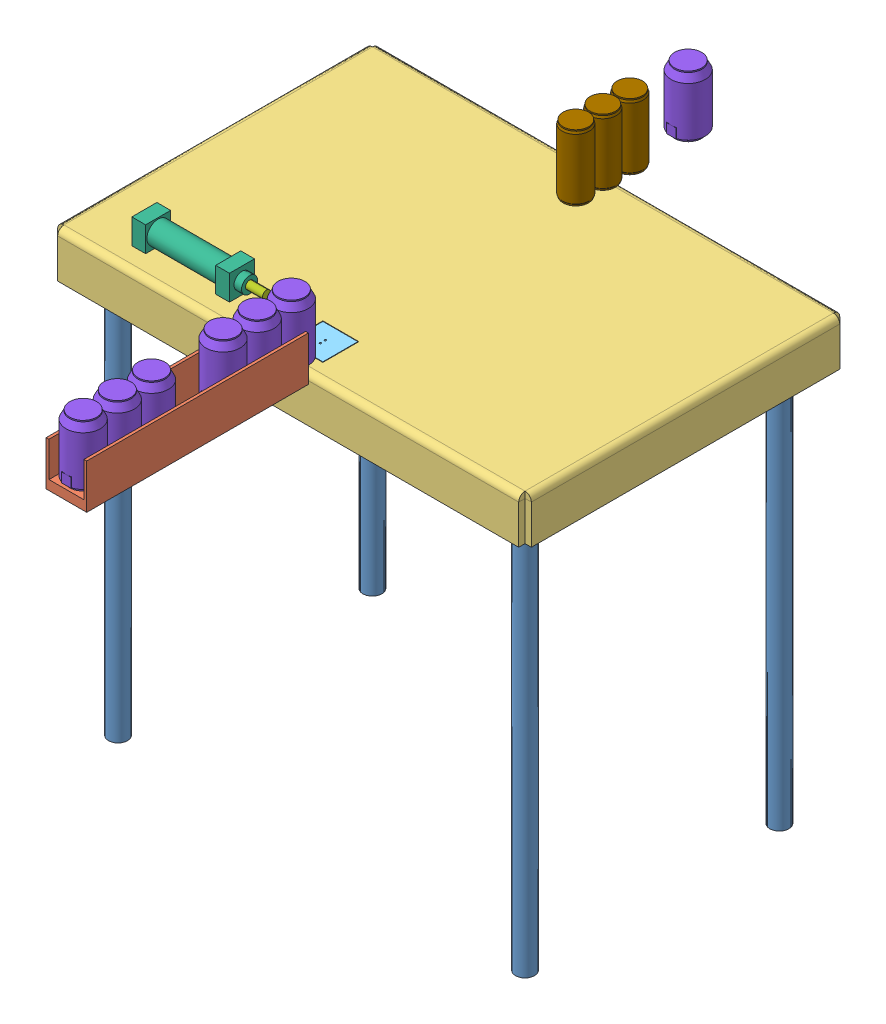
SolidWorks assembly Full_Assembly_v3, configuration Default. Lengths in mm.
Overall size (946.15 1065.21 1276.53).
18 component instances, 9 part files, 53 mates.
Components (placement in the parent):
- M37 Metal Table-1: M37 Metal Table [Default] at (-122.75 340.8931 1031.9817) size (914.4 863.6 609.6)
- Goose Output-1: Goose Output [Default] at (293.9688 417.0931 1047.8567) size (80.96 88.9 442.73)
- Table Topper-1: Table Topper [Default] at (-125.925 345.3431 1035.1567) size (946.15 90.8 641.35)
- Load Cell Assembly-1: Load Cell Assembly [Default] at (309.0555 378.227 899.7114) size (69.85 26.2 103.99)
  - Load Cell and Brace-1: Load Cell and Brace [Default] at (-9.1055 31.7162 92.7424) size (69 14.2 83)
  - scalePlate_v2_234-1: scalePlate_v2_234 [Default] at (-9.5305 57.9162 113.7283) x (0 0 -1) z (-1 0 0) size (69.85 12 69.85)
- Cylinder-1: Cylinder [Default] at (-22.0508 486.1431 953.5147) x (0 0 1) z (1 0 0) size (50 50 210)
- Rod-1: Rod [Default] at (221.9492 461.1431 978.5147) x (0 0.637822 -0.770184) z (0 0.770184 0.637822) size (16 134 16)
- can355mL-1: can355mL [Default] at (334.45 436.1431 1041.3967) x (0 0 -1) z (1 0 0) size (68.26 122.24 68.26)
- can355mL-2: can355mL [Default] at (334.45 436.1431 1177.9217) x (0 0 -1) z (1 0 0) size (68.26 122.24 68.26)
- can355mL-3: can355mL [Default] at (334.45 436.1431 1109.6592) x (0 0 -1) z (1 0 0) size (68.26 122.24 68.26)
- can250mL-1: can250mL [Default] at (334.45 436.1431 473.4181) x (0.051367 0 -0.99868) z (0.99868 0 0.051367) size (53.98 131.76 53.98)
- can250mL-2: can250mL [Default] at (334.45 436.1431 419.4431) x (0.934155 0 -0.356866) z (0.356866 0 0.934155) size (53.98 131.76 53.98)
- can250mL-3: can250mL [Default] at (334.45 436.1431 365.4681) x (0.679338 0 0.733825) z (-0.733825 0 0.679338) size (53.98 131.76 53.98)
- can355mL-7: can355mL [Default] at (334.45 436.1431 248.9838) x (0 0 -1) z (1 0 0) size (68.26 122.24 68.26)
- can355mL-8: can355mL [Default] at (334.45 436.1431 1457.2524) x (0 0 -1) z (1 0 0) size (68.26 122.24 68.26)
- can355mL-9: can355mL [Default] at (334.45 436.1431 1320.7274) x (0 0 -1) z (1 0 0) size (68.26 122.24 68.26)
- can355mL-10: can355mL [Default] at (334.45 436.1431 1388.9899) x (0 0 -1) z (1 0 0) size (68.26 122.24 68.26)
Mates (geometry in assembly coordinates):
- Width1: width aligned: plane of M37 Metal Table-1 through (791.65 366.2931 1031.9817) normal (1 0 0); plane of Table Topper-1 through (-122.75 366.2931 1031.9817) normal (-1 0 0); plane of M37 Metal Table-1 through (807.525 423.4431 1035.1567) normal (1 0 0); plane of Table Topper-1 through (-138.625 423.4431 1035.1567) normal (-1 0 0)
- Width2: width aligned: plane of M37 Metal Table-1 through (-122.75 366.2931 1031.9817) normal (0 0 1); plane of Table Topper-1 through (-122.75 366.2931 422.3817) normal (0 0 -1); plane of M37 Metal Table-1 through (-125.925 423.4431 1047.8567) normal (0 0 1); plane of Table Topper-1 through (-125.925 423.4431 406.5067) normal (0 0 -1)
- Distance1: distance = 863.6 mm aligned: plane of M37 Metal Table-1 through (-122.75 -446.5069 1031.9817) normal (0 -1 0); plane of Goose Output-1 through (374.9313 417.0931 1490.5914) normal (0 -1 0)
- LimitDistance1: limit distance = 432.5938 mm aligned: plane of Goose Output-1 through (374.9313 505.9931 1490.5914) normal (1 0 0); plane of Table Topper-1 through (807.525 423.4431 1035.1567) normal (1 0 0)
- LimitDistance2: limit distance = 432.5938 mm aligned: plane of Table Topper-1 through (-138.625 423.4431 1035.1567) normal (-1 0 0); plane of Goose Output-1 through (293.9688 417.0931 1490.5914) normal (-1 0 0)
- Parallel1: parallel aligned: plane of Goose Output-1 through (299.525 436.1431 1490.5914) normal (0 1 0); plane of Table Topper-1 through (-125.925 436.1431 1035.1567) normal (0 1 0)
- Coincident5: coincident aligned: plane of Goose Output-1 through (299.525 436.1431 1490.5914) normal (0 1 0); plane of Table Topper-1 through (-125.925 436.1431 1035.1567) normal (0 1 0)
- Coincident7: coincident aligned: plane of Table Topper-1 through (-125.925 436.1431 1035.1567) normal (0 1 0); plane of Load Cell Assembly-1/scalePlate_v2_234-1 through (299.525 436.1431 1013.4397) normal (0 1 0)
- Concentric1: concentric anti-aligned: cylinder of Cylinder-1 through (187.9492 461.1431 978.5147) axis (-1 0 0) radius 16; cylinder of Rod-1 through (87.9492 461.1431 978.5147) axis (1 0 0) radius 8
- LimitDistance3: limit distance = 34 mm aligned: plane of Rod-1 through (221.9492 461.1431 978.5147) normal (1 0 0); plane of Cylinder-1 through (187.9492 461.1431 978.5147) normal (1 0 0)
- Parallel2: parallel anti-aligned: plane of Table Topper-1 through (-125.925 423.4431 1047.8567) normal (0 0 1); plane of Cylinder-1 through (172.9492 486.1431 953.5147) normal (0 0 -1)
- Coincident9: coincident anti-aligned: plane of Table Topper-1 through (-125.925 436.1431 1035.1567) normal (0 1 0); plane of Cylinder-1 through (5.4492 436.1431 953.5147) normal (0 -1 0)
- Width3: width anti-aligned: plane of Goose Output-1 through (374.9313 505.9931 1490.5914) normal (1 0 0); plane of Load Cell Assembly-1/scalePlate_v2_234-1 through (293.9688 417.0931 1490.5914) normal (-1 0 0); plane of Goose Output-1 through (299.525 432.1431 1013.4397) normal (-1 0 0); plane of Load Cell Assembly-1/scalePlate_v2_234-1 through (369.375 432.1431 1013.4397) normal (1 0 0)
- Width4: width anti-aligned: plane of Cylinder-1 through (172.9492 486.1431 953.5147) normal (0 0 -1); plane of Load Cell Assembly-1/scalePlate_v2_234-1 through (172.9492 486.1431 1003.5147) normal (0 0 1); plane of Cylinder-1 through (299.525 432.1431 1013.4397) normal (0 0 1); plane of Load Cell Assembly-1/scalePlate_v2_234-1 through (299.525 432.1431 943.5897) normal (0 0 -1)
- Width5: width anti-aligned: plane of Table Topper-1 through (807.525 423.4431 1035.1567) normal (1 0 0); plane of Load Cell Assembly-1/scalePlate_v2_234-1 through (-138.625 423.4431 1035.1567) normal (-1 0 0); plane of Table Topper-1 through (299.525 432.1431 1013.4397) normal (-1 0 0); plane of Load Cell Assembly-1/scalePlate_v2_234-1 through (369.375 432.1431 1013.4397) normal (1 0 0)
- Coincident11: coincident anti-aligned: plane of Table Topper-1 through (-125.925 436.1431 1035.1567) normal (0 1 0); plane of can250mL-1 through (335.7548 436.1431 448.0516) normal (0 -1 0)
- Coincident18: coincident anti-aligned: plane of Table Topper-1 through (-125.925 436.1431 1035.1567) normal (0 1 0); plane of can355mL-2 through (334.45 436.1431 1150.9342) normal (0 -1 0)
- Coincident19: coincident anti-aligned: plane of Table Topper-1 through (-125.925 436.1431 1035.1567) normal (0 1 0); plane of can355mL-3 through (334.45 436.1431 1082.6717) normal (0 -1 0)
- Tangent5: tangent anti-aligned: cylinder of can355mL-2 through (334.45 436.1431 1177.9217) axis (0 -1 0) radius 34.1313; cylinder of can355mL-3 through (334.45 436.1431 1109.6592) axis (0 -1 0) radius 34.1313
- Width6: width: plane of Goose Output-1 through (299.525 505.9931 1490.5914) normal (1 0 0); plane of can250mL-1 through (369.375 436.1431 1490.5914) normal (-1 0 0); cylinder of Goose Output-1 through (334.45 436.1431 473.4181) axis (0 -1 0) radius 26.9875
- Width8: width: plane of Goose Output-1 through (369.375 436.1431 1490.5914) normal (-1 0 0); plane of can355mL-2 through (299.525 505.9931 1490.5914) normal (1 0 0); cylinder of Goose Output-1 through (334.45 436.1431 1177.9217) axis (0 -1 0) radius 34.1313
- Width10: width: plane of Goose Output-1 through (299.525 505.9931 1490.5914) normal (1 0 0); plane of can355mL-3 through (369.375 436.1431 1490.5914) normal (-1 0 0); cylinder of Goose Output-1 through (334.45 436.1431 1109.6592) axis (0 -1 0) radius 34.1313
- Coincident20: coincident anti-aligned: plane of Table Topper-1 through (-125.925 436.1431 1035.1567) normal (0 1 0); plane of can250mL-2 through (358.1776 436.1431 410.3787) normal (0 -1 0)
- Coincident21: coincident anti-aligned: plane of Table Topper-1 through (-125.925 436.1431 1035.1567) normal (0 1 0); plane of can250mL-3 through (351.7052 436.1431 384.1073) normal (0 -1 0)
- Tangent6: tangent anti-aligned: cylinder of can250mL-1 through (334.45 436.1431 473.4181) axis (0 -1 0) radius 26.9875; cylinder of can250mL-2 through (334.45 436.1431 419.4431) axis (0 -1 0) radius 26.9875
- Tangent7: tangent anti-aligned: cylinder of can250mL-2 through (334.45 436.1431 419.4431) axis (0 -1 0) radius 26.9875; cylinder of can250mL-3 through (334.45 436.1431 365.4681) axis (0 -1 0) radius 26.9875
- Width11: width: plane of Goose Output-1 through (299.525 505.9931 1490.5914) normal (1 0 0); plane of can250mL-2 through (369.375 436.1431 1490.5914) normal (-1 0 0); cylinder of Goose Output-1 through (334.45 436.1431 419.4431) axis (0 -1 0) radius 26.9875
- Width12: width: plane of Goose Output-1 through (299.525 505.9931 1490.5914) normal (1 0 0); plane of can250mL-3 through (369.375 436.1431 1490.5914) normal (-1 0 0); cylinder of Goose Output-1 through (334.45 436.1431 365.4681) axis (0 -1 0) radius 26.9875
- Coincident22: coincident anti-aligned: plane of Goose Output-1 through (293.9688 417.0931 1047.8567) normal (0 0 -1); plane of Table Topper-1 through (-125.925 423.4431 1047.8567) normal (0 0 1)
- Width14: width aligned: plane of Table Topper-1 through (370.391 345.3431 1014.4557) normal (-1 0 0); plane of Table Topper-1 through (298.509 345.3431 1014.4557) normal (1 0 0); plane of Load Cell Assembly-1/scalePlate_v2_234-1 through (299.525 432.1431 1013.4397) normal (-1 0 0); plane of Load Cell Assembly-1/scalePlate_v2_234-1 through (369.375 432.1431 1013.4397) normal (1 0 0)
- Width15: width anti-aligned: plane of Table Topper-1 through (298.509 345.3431 1014.4557) normal (0 0 -1); plane of Table Topper-1 through (298.509 345.3431 942.5737) normal (0 0 1); plane of Load Cell Assembly-1/scalePlate_v2_234-1 through (299.525 432.1431 1013.4397) normal (0 0 1); plane of Load Cell Assembly-1/scalePlate_v2_234-1 through (299.525 432.1431 943.5897) normal (0 0 -1)
- Width17: width: plane of Goose Output-1 through (369.375 436.1431 1490.5914) normal (-1 0 0); plane of Goose Output-1 through (299.525 505.9931 1490.5914) normal (1 0 0); cylinder of can355mL-4 through (334.45 436.1431 1259.8293) axis (0 -1 0) radius 34.1313
- Coincident31: coincident anti-aligned: plane of Table Topper-1 through (-125.925 436.1431 1035.1567) normal (0 1 0); plane of can355mL-7 through (334.45 436.1431 221.9963) normal (0 -1 0)
- Width19: width: plane of Goose Output-1 through (369.375 436.1431 1490.5914) normal (-1 0 0); plane of Goose Output-1 through (299.525 505.9931 1490.5914) normal (1 0 0); cylinder of can355mL-7 through (334.45 436.1431 248.9838) axis (0 -1 0) radius 34.1313
- Coincident33: coincident anti-aligned: plane of Table Topper-1 through (-125.925 436.1431 1035.1567) normal (0 1 0); plane of can355mL-1 through (334.45 436.1431 1014.4092) normal (0 -1 0)
- Tangent13: tangent anti-aligned: cylinder of can355mL-1 through (334.45 436.1431 1041.3967) axis (0 -1 0) radius 34.1313; cylinder of can355mL-3 through (334.45 436.1431 1109.6592) axis (0 -1 0) radius 34.1313
- Width20: width: plane of Goose Output-1 through (299.525 505.9931 1490.5914) normal (1 0 0); plane of Goose Output-1 through (369.375 436.1431 1490.5914) normal (-1 0 0); cylinder of can355mL-1 through (334.45 436.1431 1041.3967) axis (0 -1 0) radius 34.1313
- Parallel4: parallel aligned: plane of M37 Metal Table-1 through (-122.75 366.2931 1031.9817) normal (0 0 1); plane of can355mL-7 through (334.45 436.1431 283.115) normal (0 0 1)
- Parallel5: parallel aligned: plane of M37 Metal Table-1 through (-122.75 366.2931 1031.9817) normal (0 0 1); plane of can355mL-2 through (334.45 436.1431 1212.053) normal (0 0 1)
- Parallel6: parallel aligned: plane of M37 Metal Table-1 through (-122.75 366.2931 1031.9817) normal (0 0 1); plane of can355mL-3 through (334.45 436.1431 1143.7905) normal (0 0 1)
- Parallel7: parallel aligned: plane of M37 Metal Table-1 through (-122.75 366.2931 1031.9817) normal (0 0 1); plane of can355mL-1 through (334.45 436.1431 1075.528) normal (0 0 1)
- LimitDistance14: limit distance = 792.4129 mm aligned: plane of can355mL-7 through (334.45 436.1431 283.115) normal (0 0 1); plane of can355mL-1 through (334.45 436.1431 1075.528) normal (0 0 1)
- Tangent14: tangent anti-aligned: cylinder of can355mL-9 through (334.45 436.1431 1320.7274) axis (0 -1 0) radius 34.1313; cylinder of can355mL-10 through (334.45 436.1431 1388.9899) axis (0 -1 0) radius 34.1313
- Tangent15: tangent anti-aligned: cylinder of can355mL-8 through (334.45 436.1431 1457.2524) axis (0 -1 0) radius 34.1313; cylinder of can355mL-10 through (334.45 436.1431 1388.9899) axis (0 -1 0) radius 34.1313
- Coincident38: coincident anti-aligned: plane of Table Topper-1 through (-125.925 436.1431 1035.1567) normal (0 1 0); plane of can355mL-8 through (334.45 436.1431 1430.2649) normal (0 -1 0)
- Coincident39: coincident aligned: plane of can355mL-9 through (334.45 436.1431 1293.7399) normal (0 -1 0); plane of can355mL-10 through (334.45 436.1431 1362.0024) normal (0 -1 0)
- Coincident40: coincident anti-aligned: plane of Table Topper-1 through (-125.925 436.1431 1035.1567) normal (0 1 0); plane of can355mL-10 through (334.45 436.1431 1362.0024) normal (0 -1 0)
- Width21: width: plane of Goose Output-1 through (299.525 505.9931 1490.5914) normal (1 0 0); plane of can355mL-8 through (369.375 436.1431 1490.5914) normal (-1 0 0); cylinder of Goose Output-1 through (334.45 436.1431 1457.2524) axis (0 -1 0) radius 34.1313
- Width22: width: plane of Goose Output-1 through (374.9313 505.9931 1490.5914) normal (1 0 0); plane of can355mL-10 through (293.9688 417.0931 1490.5914) normal (-1 0 0); cylinder of Goose Output-1 through (334.45 436.1431 1388.9899) axis (0 -1 0) radius 34.1313
- Width23: width: plane of Goose Output-1 through (374.9313 505.9931 1490.5914) normal (1 0 0); plane of can355mL-9 through (293.9688 417.0931 1490.5914) normal (-1 0 0); cylinder of Goose Output-1 through (334.45 436.1431 1320.7274) axis (0 -1 0) radius 34.1313
- LimitDistance15: limit distance = 142.8057 mm aligned: plane of can355mL-9 through (334.45 436.1431 1354.8587) normal (0 0 1); plane of can355mL-2 through (334.45 436.1431 1212.053) normal (0 0 1)
- Parallel8: parallel aligned: plane of M37 Metal Table-1 through (-122.75 366.2931 1031.9817) normal (0 0 1); plane of can355mL-8 through (334.45 436.1431 1491.3837) normal (0 0 1)
- Parallel10: parallel aligned: plane of M37 Metal Table-1 through (-122.75 366.2931 1031.9817) normal (0 0 1); plane of can355mL-10 through (334.45 436.1431 1423.1212) normal (0 0 1)
